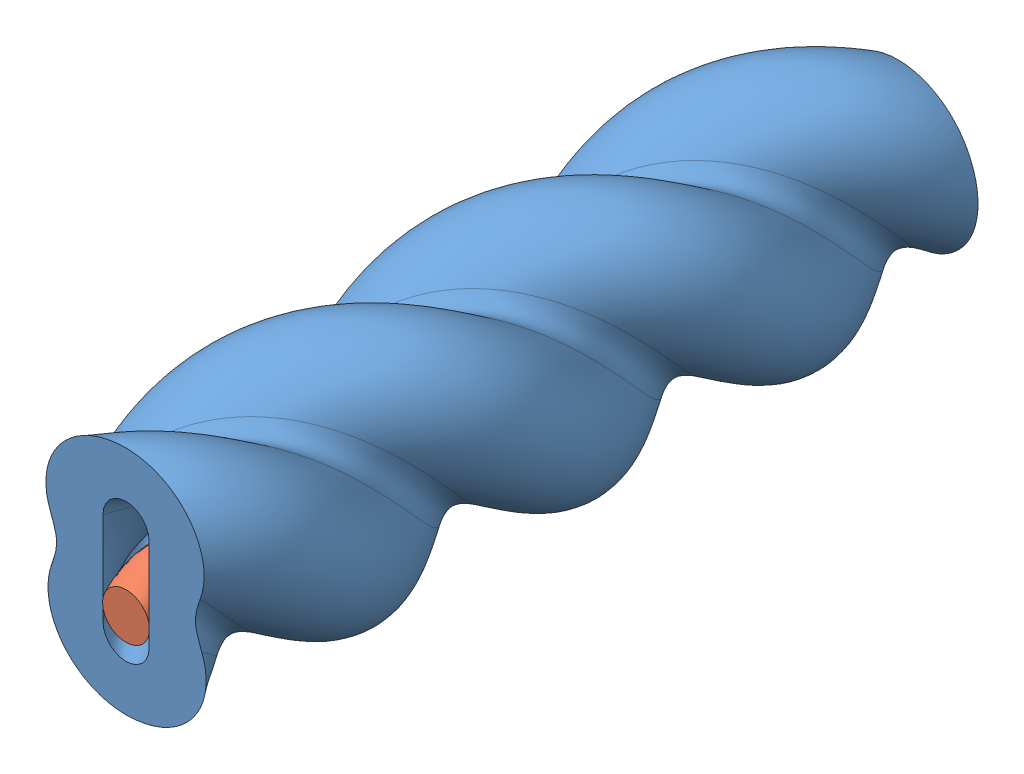
SolidWorks assembly Assem1, configuration Default. Lengths in mm.
Overall size (16.12 16.72 51.5).
2 component instances, 2 part files, 2 mates.
Components (placement in the parent):
- hOUSING2-1: hOUSING2 [Default] at (40.1741 51.4293 55.2317) size (16.12 16.72 51.5)
- 2hdlix-2: 2hdlix [Default] at (41.683 49.8661 55.2098) x (-0.310313 0.950504 0.015748) z (0.017967 -0.010699 0.999781) size (10.19 10.08 50.8)
Mates (geometry in assembly coordinates):
- Coincident35: coincident: line of hOUSING2-1 through (42.9236 53.017 4.4317) axis (-0.865978 -0.500081 0); point of 2hdlix-2
- Coincident36: coincident: line of hOUSING2-1 through (40.1741 54.6043 55.2317) axis (0 -1 0); point of 2hdlix-2
